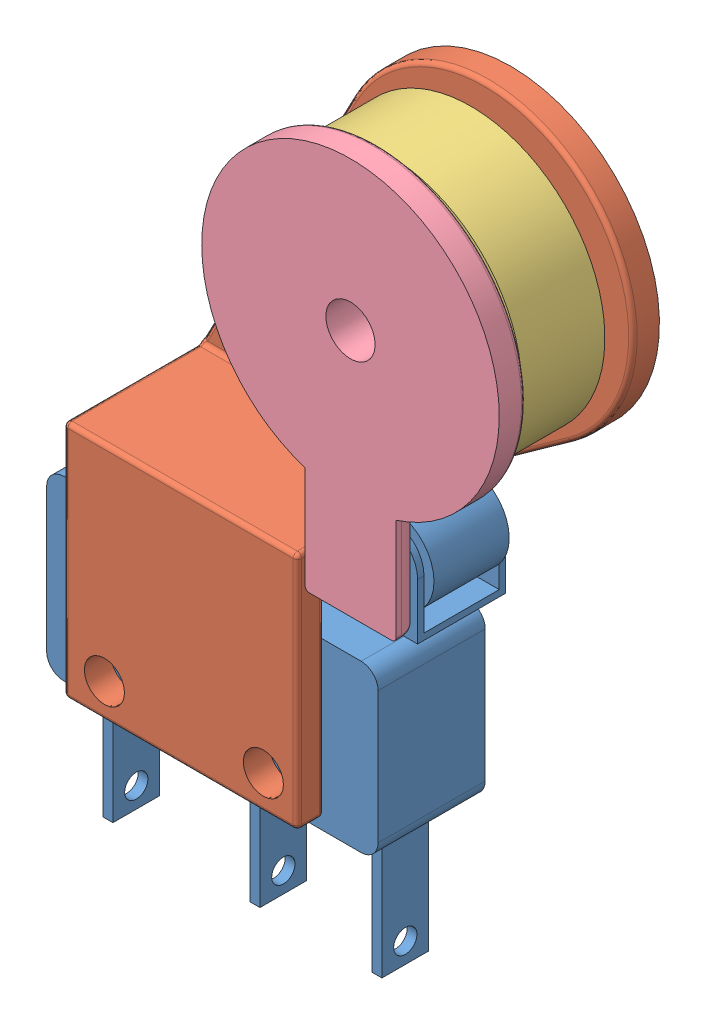
SolidWorks assembly Filament Runout assembly, configuration Default. Lengths in mm.
Overall size (30.9 47.3 9.78).
4 component instances, 4 part files, 8 mates.
Components (placement in the parent):
- roller switch-1: roller switch [Default] at (1.4793 13.0699 24.1671) size (22.2 25.64 6.4)
- housing-1: housing [Default] at (18.1671 16.6785 27.9504) x (0 0 1) z (-1 0 0) size (9.78 36.24 25.83)
- bearing-1: bearing [Default] at (21.1389 41.2795 24.8656) x (0.781493 -0.623914 0) z (0 0 1) size (16 16 4.98)
- bearing grip-1: bearing grip [Default] at (21.1389 41.2795 28.701) size (17.78 23.7 4.51)
Mates (geometry in assembly coordinates):
- Concentric1: concentric aligned: cylinder of roller switch-1 through (16.1351 15.9655 30.5679) axis (0 0 -1) radius 1.1938; cylinder of housing-1 through (16.1351 15.9655 32.2697) axis (0 0 -1) radius 1.2
- Concentric2: concentric aligned: cylinder of roller switch-1 through (6.6355 15.9655 30.5679) axis (0 0 -1) radius 1.1938; cylinder of housing-1 through (6.6355 15.9655 32.2697) axis (0 0 -1) radius 1.2
- Distance1: distance = 0.1143 mm anti-aligned: plane of roller switch-1 through (20.2753 21.9599 30.5679) normal (0 0 1); plane of housing-1 through (4.1971 13.9335 30.6822) normal (0 0 -1)
- Concentric5: concentric aligned: cylinder of housing-1 through (21.1389 41.2795 57.9754) axis (0 0 -1) radius 8.89; cylinder of bearing-1 through (21.1389 41.2795 29.844) axis (0 0 -1) radius 8.001
- Coincident8: coincident anti-aligned: plane of housing-1 through (21.1389 28.3255 24.8656) normal (0 0 1); plane of bearing-1 through (21.1389 41.2795 24.8656) normal (0 0 -1)
- Concentric6: concentric aligned: cylinder of housing-1 through (21.1389 41.2795 28.6756) axis (0 0 1) radius 1.4732; cylinder of bearing grip-1 through (21.1389 41.2795 32.0665) axis (0 0 1) radius 1.4732
- Parallel4: parallel anti-aligned: plane of housing-1 through (22.4089 45.2165 27.4056) normal (-1 0 0); plane of bearing grip-1 through (22.2819 45.2175 29.844) normal (1 0 0)
- Coincident10: coincident anti-aligned: plane of bearing-1 through (21.1389 41.2795 29.844) normal (0 0 1); plane of bearing grip-1 through (21.1389 41.2795 29.844) normal (0 0 -1)
